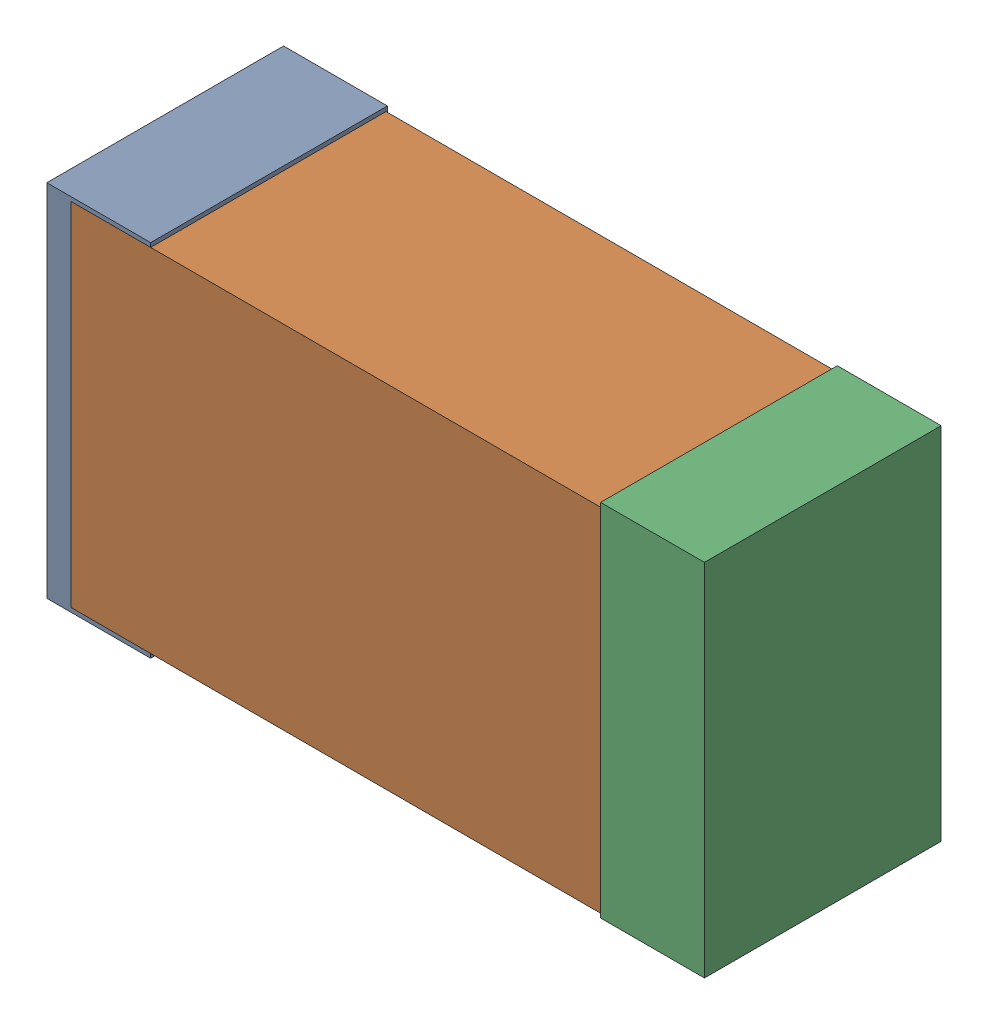
SolidWorks assembly USB23_C10, configuration Default. Lengths in mm.
Overall size (2.38 1.3 0.85).
6 component instances, 2 part files, 0 mates.
Components (placement in the parent):
- 384311232-1: 384311232 [Default] at (172.99 57.785 -1.9574) size (0.38 1.3 0.85)
  - Extruded_8-1: Extruded_8 [Default] at origin size (0.38 1.3 0.85)
- 402662800-1: 402662800 [Default] at (173.99 57.785 -1.9524) size (2.2 1.27 0.85)
  - Extruded_30-1: Extruded_30 [Default] at origin size (2.2 1.27 0.85)
- 384311232-2: 384311232 [Default] at (174.99 57.785 -1.9574) size (0.38 1.3 0.85)
  - Extruded_8-1: Extruded_8 [Default] at origin size (0.38 1.3 0.85)
